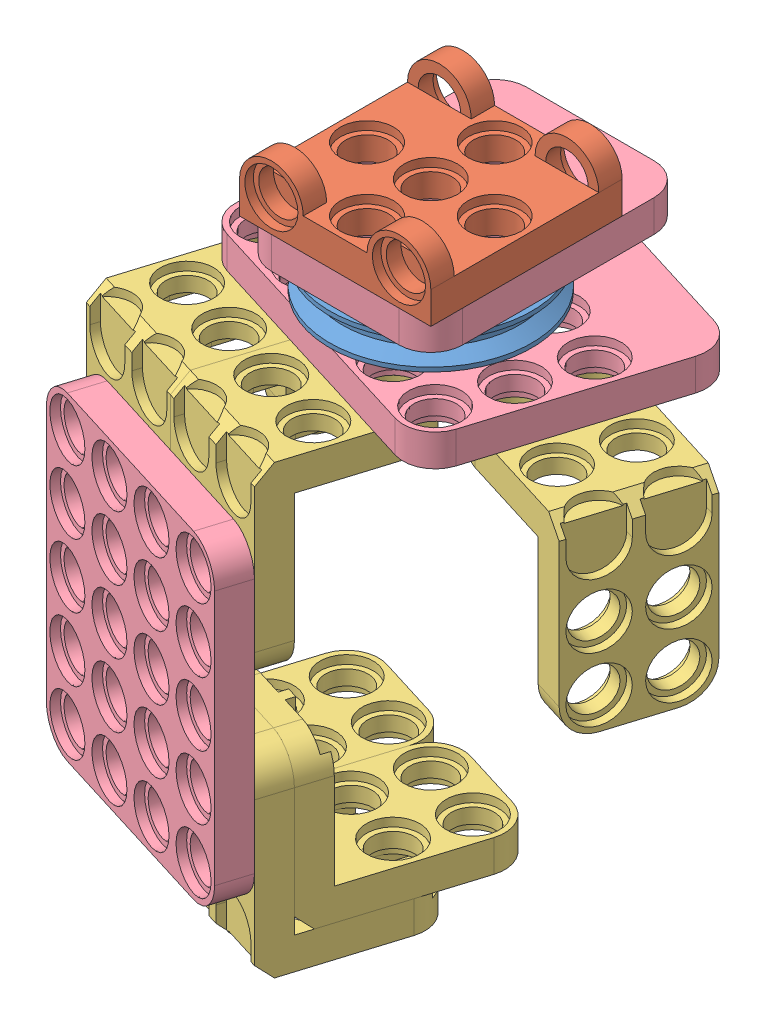
SolidWorks assembly hand, configuration Default. Lengths in mm.
Overall size (46.13 57 41.49).
13 component instances, 4 part files, 34 mates.
Components (placement in the parent):
- wheel-1: wheel [Default] at origin size (19 3 19)
- square_piece-1: square_piece [Default] at (4.5 6.75 -9) x (0 0 1) z (-1 0 0) size (18 6 18)
- l_piece-1: l_piece [Default] at (-9.142 -5.25 -5.9728) x (0 -1 0) z (-0.295919 0 0.955213) size (18 15 12)
- l_piece-2: l_piece [Default] at (16.6488 -5.25 2.017) x (0 -1 0) z (0.295919 0 -0.955213) size (18 15 12)
- l_piece-4: l_piece [Default] at (-11.7041 -5.25 7.3665) x (0 -1 0) z (0.955213 0 0.295919) size (18 15 12)
- l_piece-5: l_piece [Default] at (-0.2415 -5.25 10.9175) x (0 -1 0) z (0.955213 0 0.295919) size (18 15 12)
- l_piece-6: l_piece [Default] at (-11.7041 -47.25 7.3665) x (0 1 0) z (-0.955213 0 -0.295919) size (18 15 12)
- l_piece-7: l_piece [Default] at (-0.2415 -47.25 10.9175) x (0 1 0) z (-0.955213 0 -0.295919) size (18 15 12)
- l_piece-8: l_piece [Default] at (-13.0357 -36.75 11.6649) x (0.295919 0 -0.955213) z (0.955213 0 0.295919) size (18 15 12)
- l_piece-9: l_piece [Default] at (-1.5731 -36.75 15.216) x (0.295919 0 -0.955213) z (0.955213 0 0.295919) size (18 15 12)
- SPD-4: SPD [3B3] at (0.0005 2.25 -3) x (-1 0 -0.000151) z (0.000151 0 -1) size (18 3 24)
- SPD-5: SPD [3B5] at (0.8878 -3.75 -2.8656) x (-0.955213 0 -0.295919) z (0.295919 0 -0.955213) size (30 3 24)
- SPD-9: SPD [4B5] at (-8.6361 -26.25 17.7389) x (0 1 0) z (0.955213 0 0.295919) size (30 3 24)
Mates (geometry in assembly coordinates):
- Coincident1: coordinate: point of wheel-1
- Concentric1: concentric aligned: cylinder of wheel-1 through (0 0.75 0) axis (0 1 0) radius 2; cylinder of square_piece-1 through (0 6.75 0) axis (0 1 0) radius 2
- Coincident19: coincident anti-aligned: plane of l_piece-4 through (-5.9728 -5.25 9.142) normal (0.955213 0 0.295919); plane of l_piece-5 through (-5.9728 -5.25 9.142) normal (-0.955213 0 -0.295919)
- Concentric23: concentric anti-aligned: cylinder of l_piece-6 through (-15.9013 -32.25 10.7772) axis (0.295919 0 -0.955213) radius 2; cylinder of l_piece-8 through (-15.9013 -32.25 10.7772) axis (-0.295919 0 0.955213) radius 2
- Concentric24: concentric anti-aligned: cylinder of l_piece-6 through (-10.1701 -32.25 12.5527) axis (0.295919 0 -0.955213) radius 2; cylinder of l_piece-8 through (-10.1701 -32.25 12.5527) axis (-0.295919 0 0.955213) radius 2
- Coincident24: coincident anti-aligned: plane of l_piece-6 through (-18.767 -29.25 9.8894) normal (0.295919 0 -0.955213); plane of l_piece-8 through (-7.3044 -29.25 13.4404) normal (-0.295919 0 0.955213)
- Concentric25: concentric anti-aligned: cylinder of l_piece-7 through (1.2925 -32.25 16.1037) axis (0.295919 0 -0.955213) radius 2; cylinder of l_piece-9 through (1.2925 -32.25 16.1037) axis (-0.295919 0 0.955213) radius 2
- Coincident25: coincident anti-aligned: plane of l_piece-7 through (-7.3044 -29.25 13.4404) normal (0.295919 0 -0.955213); plane of l_piece-9 through (4.1581 -29.25 16.9915) normal (-0.295919 0 0.955213)
- Concentric26: concentric aligned: cylinder of square_piece-1 through (0 6.75 0) axis (0 1 0) radius 2; cylinder of SPD-4 through (0 0.75 0) axis (0 1 0) radius 2
- Coincident26: coincident anti-aligned: plane of square_piece-1 through (4.5 3.75 -9) normal (0 -1 0); plane of SPD-4 through (0.0005 3.75 -3) normal (0 1 0)
- Concentric27: concentric aligned: cylinder of l_piece-1 through (-9.687 -5.25 -9.2823) axis (0 1 0) radius 2; cylinder of SPD-5 through (-9.687 -5.25 -9.2823) axis (0 1 0) radius 2
- Concentric28: concentric aligned: cylinder of l_piece-1 through (-11.4626 -5.25 -3.551) axis (0 1 0) radius 2; cylinder of SPD-5 through (-11.4626 -5.25 -3.551) axis (0 1 0) radius 2
- Coincident28: coincident anti-aligned: plane of l_piece-1 through (-3.7534 -5.25 1.9779) normal (0 1 0); plane of SPD-5 through (0.8878 -5.25 -2.8656) normal (0 -1 0)
- Coincident30: coincident anti-aligned: plane of wheel-1 through (0 0.75 0) normal (0 1 0); plane of SPD-4 through (0.0005 0.75 -3) normal (0 -1 0)
- Concentric33: concentric aligned: cylinder of wheel-1 through (0 0.75 0) axis (0 1 0) radius 2; cylinder of SPD-5 through (0 -5.25 0) axis (0 1 0) radius 2
- Coincident32: coincident anti-aligned: plane of wheel-1 through (0 -2.25 0) normal (0 -1 0); plane of SPD-5 through (0.8878 -2.25 -2.8656) normal (0 1 0)
- Concentric34: concentric aligned: cylinder of l_piece-4 through (-13.2381 -5.25 2.1802) axis (0 1 0) radius 2; cylinder of SPD-5 through (-13.2381 -5.25 2.1802) axis (0 1 0) radius 2
- Coincident33: coincident anti-aligned: plane of l_piece-4 through (-3.7534 -5.25 1.9779) normal (0 1 0); plane of SPD-5 through (0.8878 -5.25 -2.8656) normal (0 -1 0)
- Concentric38: concentric aligned: cylinder of l_piece-5 through (-1.7755 -5.25 5.7313) axis (0 1 0) radius 2; cylinder of SPD-5 through (-1.7755 -5.25 5.7313) axis (0 1 0) radius 2
- Concentric39: concentric aligned: cylinder of l_piece-5 through (3.9558 -5.25 7.5068) axis (0 1 0) radius 2; cylinder of SPD-5 through (3.9558 -5.25 7.5068) axis (0 1 0) radius 2
- Coincident34: coincident anti-aligned: plane of l_piece-5 through (7.7092 -5.25 5.5289) normal (0 1 0); plane of SPD-5 through (0.8878 -5.25 -2.8656) normal (0 -1 0)
- Concentric41: concentric aligned: cylinder of l_piece-2 through (11.4626 -5.25 3.551) axis (0 1 0) radius 2; cylinder of SPD-5 through (11.4626 -5.25 3.551) axis (0 1 0) radius 2
- Concentric42: concentric aligned: cylinder of l_piece-2 through (13.2381 -5.25 -2.1802) axis (0 1 0) radius 2; cylinder of SPD-5 through (13.2381 -5.25 -2.1802) axis (0 1 0) radius 2
- Coincident35: coincident anti-aligned: plane of l_piece-2 through (11.2602 -5.25 -5.9336) normal (0 1 0); plane of SPD-5 through (0.8878 -5.25 -2.8656) normal (0 -1 0)
- Concentric43: concentric anti-aligned: cylinder of l_piece-4 through (-15.9013 -14.25 10.7772) axis (0.295919 0 -0.955213) radius 2; cylinder of SPD-9 through (-16.7891 -14.25 13.6428) axis (-0.295919 0 0.955213) radius 2
- Concentric44: concentric anti-aligned: cylinder of l_piece-4 through (-10.1701 -14.25 12.5527) axis (0.295919 0 -0.955213) radius 2; cylinder of SPD-9 through (-11.0578 -14.25 15.4183) axis (-0.295919 0 0.955213) radius 2
- Coincident36: coincident anti-aligned: plane of l_piece-4 through (-8.1922 -5.25 16.3061) normal (-0.295919 0 0.955213); plane of SPD-9 through (-8.1922 -26.25 16.3061) normal (0.295919 0 -0.955213)
- Concentric45: concentric aligned: cylinder of l_piece-8 through (-15.9013 -32.25 10.7772) axis (-0.295919 0 0.955213) radius 2; cylinder of SPD-9 through (-16.7891 -32.25 13.6428) axis (-0.295919 0 0.955213) radius 2
- Concentric46: concentric aligned: cylinder of l_piece-8 through (-10.1701 -32.25 12.5527) axis (-0.295919 0 0.955213) radius 2; cylinder of SPD-9 through (-11.0578 -32.25 15.4183) axis (-0.295919 0 0.955213) radius 2
- Coincident37: coincident anti-aligned: plane of l_piece-6 through (-19.6547 -47.25 12.755) normal (-0.295919 0 0.955213); plane of SPD-9 through (-8.1922 -26.25 16.3061) normal (0.295919 0 -0.955213)
- Concentric47: concentric anti-aligned: cylinder of l_piece-7 through (1.2925 -32.25 16.1037) axis (0.295919 0 -0.955213) radius 2; cylinder of SPD-9 through (0.4047 -32.25 18.9693) axis (-0.295919 0 0.955213) radius 2
- Coincident38: coincident anti-aligned: plane of l_piece-7 through (-8.1922 -47.25 16.3061) normal (-0.295919 0 0.955213); plane of SPD-9 through (-8.1922 -26.25 16.3061) normal (0.295919 0 -0.955213)
- Concentric50: concentric anti-aligned: cylinder of l_piece-7 through (-4.4388 -32.25 14.3282) axis (0.295919 0 -0.955213) radius 2; cylinder of SPD-9 through (-5.3265 -32.25 17.1938) axis (-0.295919 0 0.955213) radius 2
- LimitAngle3: limit planar angle = 1.270379 rad anti-aligned: plane of SPD-5 through (0.8878 -3.75 -2.8656) normal (-0.955213 0 -0.295919)
